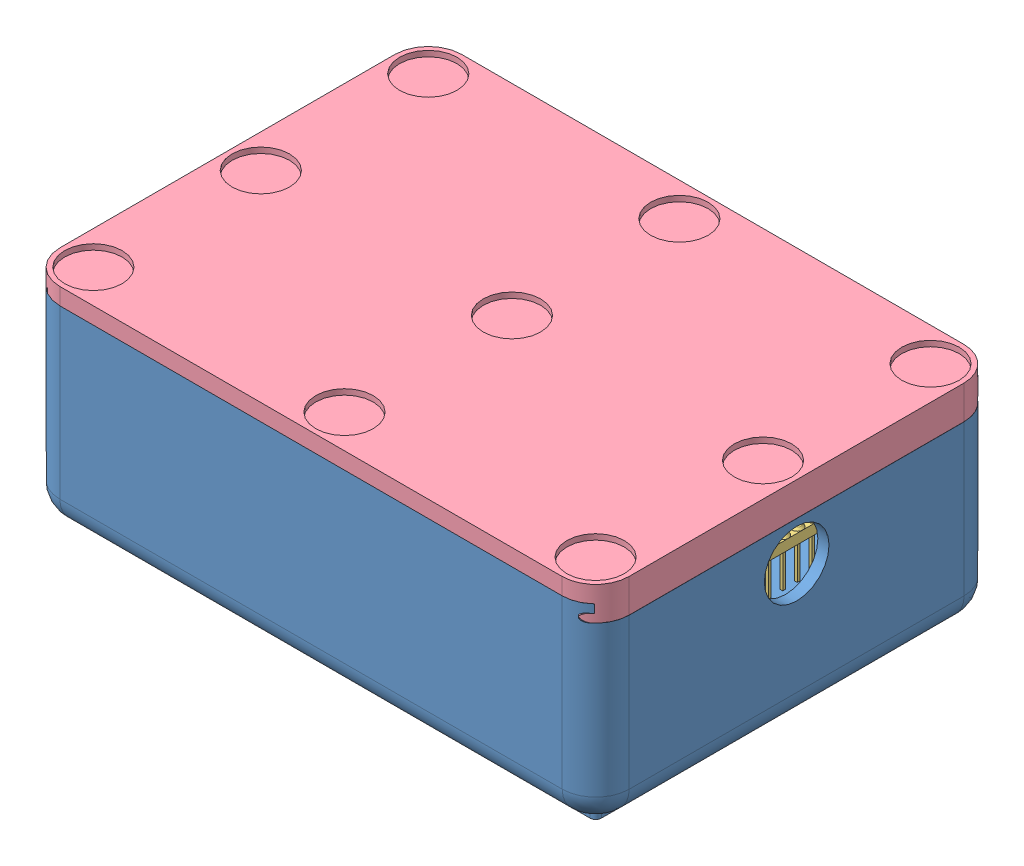
SolidWorks assembly tank sensor, configuration Default. Lengths in mm.
Overall size (102 46.25 72).
4 component instances, 4 part files, 8 mates.
Components (placement in the parent):
- Body-1: Body [Default] at (31.0251 36.3418 84.994) size (102 37.01 72)
- Ultrasonic-sensor-1: Ultrasonic-sensor [Default] at (-3.9749 36.9918 85.294) x (0 0 1) z (1 0 0) size (45.6 18.65 28.52)
- ESP-32-1: ESP-32 [Default] at (54.175 45.3649 85.7339) size (28 11.96 55.36)
- Cover^tank sensor-1: Cover^tank sensor [Default] x (0 0 -1) z (1 0 0) size (72 6 101.97) (virtual)
Mates (geometry in assembly coordinates):
- Coincident1: coincident anti-aligned: plane of Body-1 through (31.0251 35.3418 84.994) normal (0 1 0); plane of Ultrasonic-sensor-1 through (-3.9749 35.3418 85.294) normal (0 -1 0)
- Coincident2: coincident aligned: line of Body-1 through (6.4251 35.3418 62.494) axis (0 1 0); line of Ultrasonic-sensor-1 through (6.4251 35.3418 62.494) axis (0 1 0)
- Parallel1: parallel aligned: line of Body-1 through (-14.3749 35.3418 107.494) axis (0 1 0); line of Ultrasonic-sensor-1 through (-14.3749 35.3418 108.094) axis (0 1 0)
- Parallel2: parallel anti-aligned: plane of Body-1 through (-14.3749 35.3418 107.494) normal (0 0 -1); plane of Ultrasonic-sensor-1 through (6.4251 35.3418 108.094) normal (0 0 1)
- InPlace3: in place: plane of Cover^tank sensor-1 through (0 0 0) normal (1 0 0); moOrthogonalPlaneRef_w of Cover^tank sensor-1 through (0 0 0) normal (0 1 0); plane of Cover^tank sensor-1 through (0 0 0) normal (0 0 -1); unknown of Cover^tank sensor-1
- Coincident15: coincident aligned: 
- Coincident16: coincident aligned: plane of Cover^tank sensor-1 through (0 0 0) normal (0 1 0)
- Coincident17: coincident anti-aligned: plane of Cover^tank sensor-1 through (0 0 0) normal (0 0 -1)
